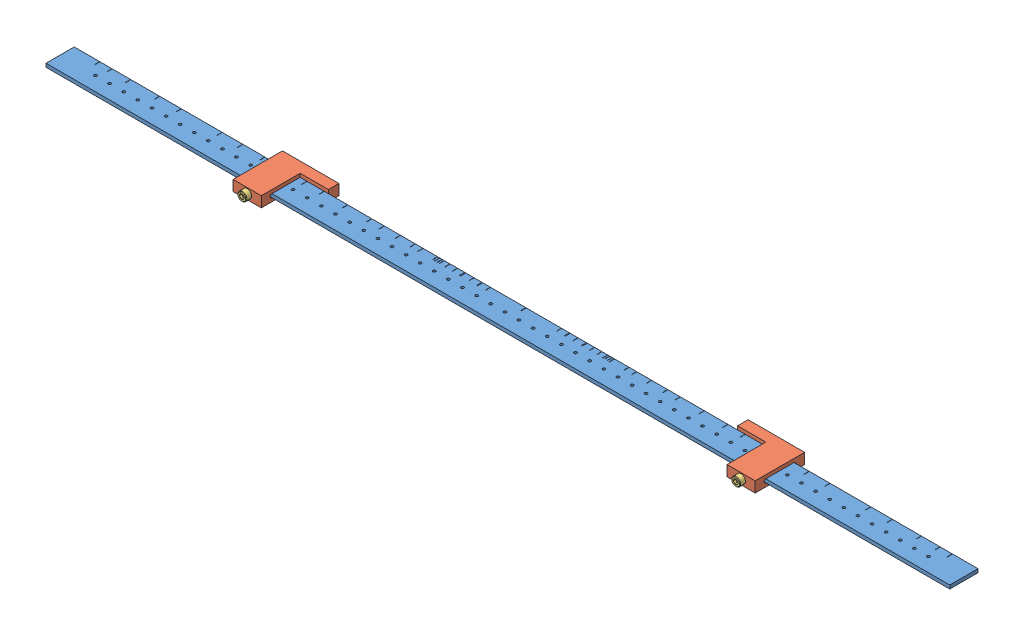
SolidWorks assembly cube_ruler, configuration Default. Lengths in mm.
Overall size (812.8 10.37 49.28).
5 component instances, 3 part files, 8 mates.
Components (placement in the parent):
- ruler_bar^cube_ruler-1: ruler_bar^cube_ruler [Default] at origin size (812.8 3.17 25.4) (virtual)
- left_stop^cube_ruler-1: left_stop^cube_ruler [Default] at (215.5597 0 -12.7) size (50.8 9.53 44.45) (virtual)
- Socket Head Cap Screw_AI-1: Socket Head Cap Screw_AI [HX-SHCS 0.19-24x0.5x0.5-N] at (228.2597 -1.5875 27.051) x (0 0 -1) z (0.92388 -0.382683 0) size (17.53 7.94 7.94)
- left_stop^cube_ruler-2: left_stop^cube_ruler [Default] at (-203.2303 -3.175 -12.7) x (-1 0 0) z (0 0 1) size (50.8 9.53 44.45) (virtual)
- Socket Head Cap Screw_AI-2: Socket Head Cap Screw_AI [HX-SHCS 0.19-24x0.5x0.5-N] at (-215.9303 -1.5875 27.051) x (0 0 -1) z (0.92388 -0.382683 0) size (17.53 7.94 7.94)
Mates (geometry in assembly coordinates):
- Coincident1: coincident anti-aligned: plane of ruler_bar^cube_ruler-1 through (-406.4 -3.175 12.7) normal (0 -1 0); plane of left_stop^cube_ruler-1 through (240.9597 -3.175 12.7) normal (0 1 0)
- Coincident2: coincident anti-aligned: plane of ruler_bar^cube_ruler-1 through (406.4 -3.175 -12.7) normal (0 0 -1); plane of left_stop^cube_ruler-1 through (190.1597 3.175 -12.7) normal (0 0 1)
- Concentric1: concentric aligned: cylinder of left_stop^cube_ruler-1 through (228.2597 -1.5875 22.225) axis (0 0 1) radius 1.8986; cylinder of Socket Head Cap Screw_AI-1 through (228.2597 -1.5875 58.801) axis (0 0 1) radius 2.413
- Coincident3: coincident anti-aligned: plane of left_stop^cube_ruler-1 through (240.9597 3.175 22.225) normal (0 0 1); plane of Socket Head Cap Screw_AI-1 through (229.7784 2.0791 22.225) normal (0 0 -1)
- Coincident4: coincident anti-aligned: plane of ruler_bar^cube_ruler-1 through (-406.4 0 12.7) normal (0 1 0); plane of left_stop^cube_ruler-2 through (-228.6303 0 12.7) normal (0 -1 0)
- Coincident5: coincident anti-aligned: plane of ruler_bar^cube_ruler-1 through (406.4 -3.175 -12.7) normal (0 0 -1); plane of left_stop^cube_ruler-2 through (-177.8303 -6.35 -12.7) normal (0 0 1)
- Concentric2: concentric aligned: cylinder of left_stop^cube_ruler-2 through (-215.9303 -1.5875 22.225) axis (0 0 1) radius 1.8986; cylinder of Socket Head Cap Screw_AI-2 through (-215.9303 -1.5875 58.801) axis (0 0 1) radius 2.413
- Coincident6: coincident anti-aligned: plane of left_stop^cube_ruler-2 through (-228.6303 -6.35 22.225) normal (0 0 1); plane of Socket Head Cap Screw_AI-2 through (-214.4116 2.0791 22.225) normal (0 0 -1)
